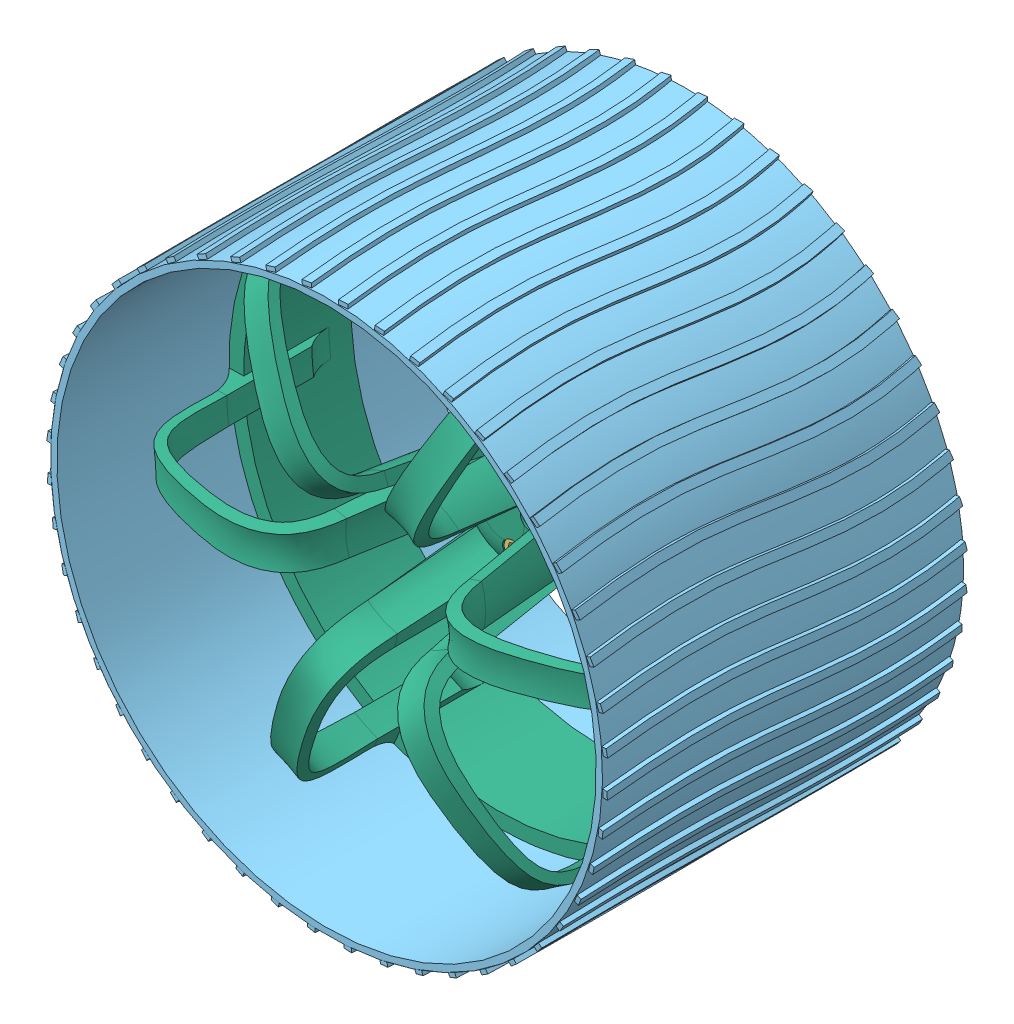
SolidWorks assembly Wheel + motor for centre, configuration Default. Lengths in mm.
Overall size (176.29 176.29 127.88).
13 component instances, 6 part files, 25 mates.
Components (placement in the parent):
- Wheel motor(RH)-1: Wheel motor(RH) [Default] at (0 -4.7975 -50.6995) size (25 25 73.38)
- connector to wheel(RH)-1: connector to wheel(RH) [Default] at (0 0 -12) x (0.944356 0.328925 0) z (0 0 -1) size (25 25 12.5)
- M3 bolt for wheels(RH)-1: M3 bolt for wheels(RH) [Default] at (6.6105 2.3025 -0.75) x (-0.928426 -0.371518 0) z (0 0 -1) size (5 5 25.25)
- M3 bolt for wheels(RH)-2: M3 bolt for wheels(RH) [Default] at (2.3025 -6.6105 -0.75) x (-0.969147 0.246485 0) z (0 0 -1) size (5 5 25.25)
- M3 bolt for wheels(RH)-3: M3 bolt for wheels(RH) [Default] at (-6.6105 -2.3025 -0.75) x (0.480752 -0.876857 0) z (0 0 -1) size (5 5 25.25)
- M3 bolt for wheels(RH)-4: M3 bolt for wheels(RH) [Default] at (-2.3025 6.6105 -0.75) x (0.142845 -0.989745 0) z (0 0 -1) size (5 5 25.25)
- M3 nut-1: M3 nut [Default] at (2.3025 -6.6105 -23.25) x (0.944356 0.328925 0) z (0 0 1) size (5 6.35 2.75)
- M3 nut-2: M3 nut [Default] at (6.6105 2.3025 -23.25) x (0.653374 0.757035 0) z (0 0 1) size (5 6.35 2.75)
- M3 nut-3: M3 nut [Default] at (-2.3025 6.6105 -23.25) x (0.187321 0.982299 0) z (0 0 1) size (5 6.35 2.75)
- M3 nut-4: M3 nut [Default] at (-6.6105 -2.3025 -23.25) x (-0.653374 -0.757035 0) z (0 0 1) size (5 6.35 2.75)
- Wheel-1: Wheel [Default] x (-0.900346 0.435176 0) z (0 0 1) size (132 132 85) (flexible)
  - Wheel Part-1-1: Wheel Part-1 [Default] at origin size (132 132 85)
  - Wheel Part-2-1: Wheel Part-2 [Default] at (0 0 -2) size (127 128.13 59.75)
Mates (geometry in assembly coordinates):
- Concentric1: concentric: cylinder of Wheel motor(RH)-1 through (0 0 -12) axis (0 0 -1) radius 2.0271; cylinder of connector to wheel(RH)-1 through (0 0 -11.999) axis (0 0 -1) radius 2.025
- Coincident3: coincident: plane of Wheel motor(RH)-1 through (0 -4.7299 -12) normal (0 0 1); plane of connector to wheel(RH)-1 through (0 0 -12) normal (0 0 1)
- Coincident4: coincident: axis of connector to wheel(RH)-1 through (6.6105 2.3025 -12) axis (0 0 -1); axis of M3 bolt for wheels(RH)-1 through (6.6105 2.3025 -24.5) axis (0 0 1)
- Coincident5: coincident: axis of connector to wheel(RH)-1 through (2.3025 -6.6105 -12) axis (0 0 -1); axis of M3 bolt for wheels(RH)-2 through (2.3025 -6.6105 -24.5) axis (0 0 1)
- Coincident6: coincident: axis of connector to wheel(RH)-1 through (-6.6105 -2.3025 -12) axis (0 0 -1); axis of M3 bolt for wheels(RH)-3 through (-6.6105 -2.3025 -24.5) axis (0 0 1)
- Coincident7: coincident: axis of connector to wheel(RH)-1 through (-2.3025 6.6105 -12) axis (0 0 -1); axis of M3 bolt for wheels(RH)-4 through (-2.3025 6.6105 -24.5) axis (0 0 1)
- Coincident8: coincident: axis of M3 bolt for wheels(RH)-4 through (-2.3025 6.6105 -24.5) axis (0 0 1); axis of M3 nut-3 through (-2.3025 6.6105 -22.8103) axis (0 0 1)
- Coincident9: coincident: axis of M3 bolt for wheels(RH)-3 through (-6.6105 -2.3025 -24.5) axis (0 0 1); axis of M3 nut-4 through (-6.6105 -2.3025 -22.8103) axis (0 0 1)
- Coincident10: coincident: axis of M3 bolt for wheels(RH)-2 through (2.3025 -6.6105 -24.5) axis (0 0 1); axis of M3 nut-1 through (2.3025 -6.6105 -22.8103) axis (0 0 1)
- Coincident11: coincident: axis of M3 bolt for wheels(RH)-1 through (6.6105 2.3025 -24.5) axis (0 0 1); axis of M3 nut-2 through (6.6105 2.3025 -23.5956) axis (0 0 -1)
- Parallel1: parallel: plane of connector to wheel(RH)-1 through (-2.3609 -0.8223 -22) normal (0.944356 0.328925 0); plane of M3 nut-3 through (-5.1381 7.1512 -22) normal (-0.944356 -0.328925 0)
- Coincident12: coincident: plane of connector to wheel(RH)-1 through (0 0 -22) normal (0 0 -1); plane of M3 nut-3 through (-2.3025 6.6105 -22) normal (0 0 1)
- Parallel2: parallel: plane of connector to wheel(RH)-1 through (-5.5943 -6.4819 -22) normal (0.653374 0.757035 0); plane of M3 nut-4 through (-9.3366 -3.252 -22) normal (-0.653374 -0.757035 0)
- Coincident13: coincident: plane of connector to wheel(RH)-1 through (0 0 -22) normal (0 0 -1); plane of M3 nut-4 through (-6.6105 -2.3025 -22) normal (0 0 1)
- Parallel4: parallel: plane of connector to wheel(RH)-1 through (3.4991 -0.6673 -22) normal (0.982299 -0.187321 0); plane of M3 nut-2 through (4.4251 4.1886 -22) normal (-0.982299 0.187321 0)
- Coincident15: coincident: plane of connector to wheel(RH)-1 through (0 0 -22) normal (0 0 -1); plane of M3 nut-2 through (6.6105 2.3025 -22) normal (0 0 1)
- Parallel5: parallel: plane of connector to wheel(RH)-1 through (-1.6039 -8.4106 -22) normal (0.187321 0.982299 0); plane of M3 nut-1 through (0.4163 -8.7959 -22) normal (-0.187321 -0.982299 0)
- Coincident16: coincident: plane of connector to wheel(RH)-1 through (0 0 -22) normal (0 0 -1); plane of M3 nut-1 through (2.3025 -6.6105 -22) normal (0 0 1)
- Concentric2: concentric: cylinder of connector to wheel(RH)-1 through (0 0 -24.5) axis (0 0 1) radius 12.5; circle of Wheel-1/Wheel Part-2-1
- Coincident21: coincident: plane of connector to wheel(RH)-1 through (0 0 -12) normal (0 0 1); plane of Wheel-1/Wheel Part-2-1 through (0 0 -12) normal (0 0 -1)
- Coincident22: coincident: axis of connector to wheel(RH)-1 through (6.6105 2.3025 -12) axis (0 0 -1); axis of Wheel-1/Wheel Part-2-1 through (6.6105 2.3025 -2) axis (0 0 -1)
- Coincident23: coincident: plane of M3 bolt for wheels(RH)-2 through (2.3025 -6.6105 -2) normal (0 0 -1); plane of Wheel-1/Wheel Part-2-1 through (0 0 -2) normal (0 0 1)
- Coincident24: coincident: plane of M3 bolt for wheels(RH)-1 through (6.6105 2.3025 -2) normal (0 0 -1); plane of Wheel-1/Wheel Part-2-1 through (6.6105 2.3025 -2) normal (0 0 1)
- Coincident25: coincident: plane of M3 bolt for wheels(RH)-4 through (-2.3025 6.6105 -2) normal (0 0 -1); plane of Wheel-1/Wheel Part-2-1 through (-2.3025 6.6105 -2) normal (0 0 1)
- Coincident26: coincident: plane of M3 bolt for wheels(RH)-3 through (-6.6105 -2.3025 -2) normal (0 0 -1); plane of Wheel-1/Wheel Part-2-1 through (-6.6105 -2.3025 -2) normal (0 0 1)
